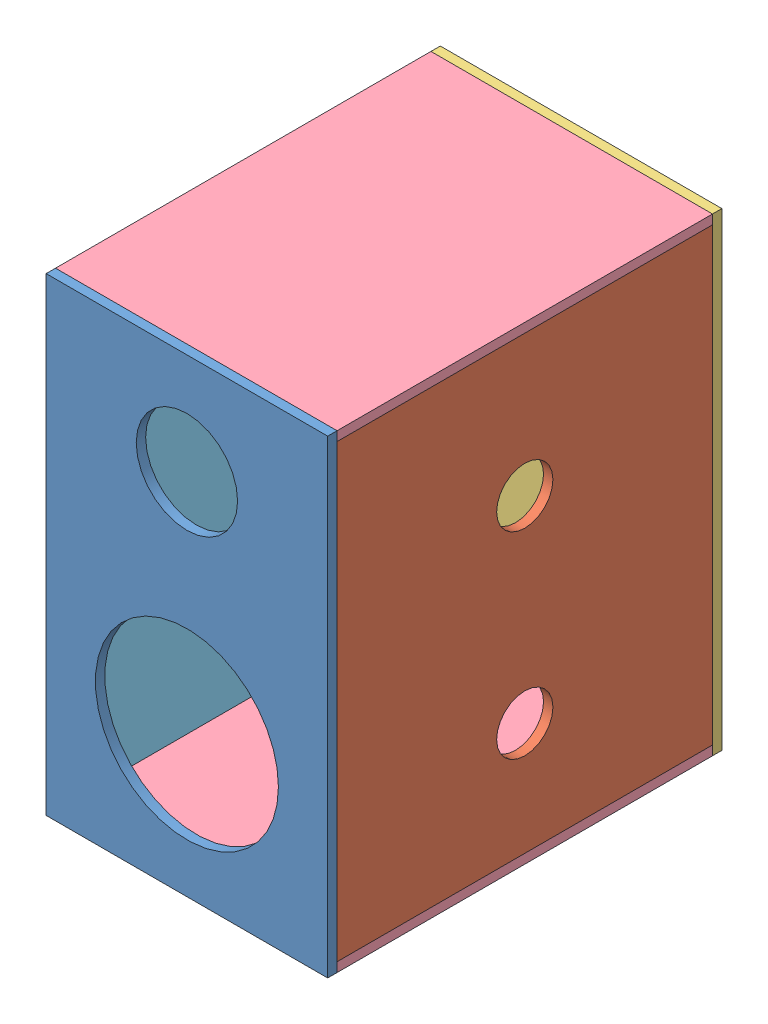
SolidWorks assembly speaker_full, configuration Default. Lengths in mm.
Overall size (300 500 420).
6 component instances, 5 part files, 13 mates.
Components (placement in the parent):
- speaker_front-1: speaker_front [Default] at origin size (300 500 10)
- speaker_int_side-1: speaker_int_side [Default] at (300 10 -410) x (0 0 1) z (-1 0 0) size (400 480 10)
- speaker_rear-1: speaker_rear [Default] at (0 0 -420) size (300 500 10)
- speaker_top_bot-1: speaker_top_bot [Default] at (0 500 -410) x (1 0 0) z (0 -1 0) size (300 400 10)
- speaker_top_bot-2: speaker_top_bot [Default] at (0 10 -410) x (1 0 0) z (0 -1 0) size (300 400 10)
- speaker_ext_side-1: speaker_ext_side [Default] at (10 455.5377 -350.3682) x (0 0 1) z (-1 0 0) size (400 480 10)
Mates (geometry in assembly coordinates):
- Coincident2: coincident aligned: line of speaker_front-1; line of speaker_int_side-1
- Coincident3: coincident anti-aligned: plane of speaker_front-1 through (0 500 -10) normal (0 0 -1); plane of speaker_int_side-1 through (290 10 -10) normal (0 0 1)
- Coincident15: coincident anti-aligned: line of speaker_int_side-1; line of speaker_rear-1
- Coincident19: coincident aligned: plane of speaker_front-1 through (0 500 -10) normal (0 1 0); plane of speaker_rear-1 through (0 500 -410) normal (0 1 0)
- Coincident20: coincident anti-aligned: line of speaker_int_side-1; line of speaker_top_bot-1
- Coincident21: coincident aligned: plane of speaker_rear-1 through (0 500 -410) normal (0 1 0); plane of speaker_top_bot-1 through (0 500 -10) normal (0 1 0)
- Coincident22: coincident: plane of speaker_rear-1 through (0 500 -410) normal (0 0 1); line of speaker_top_bot-1
- Coincident24: coincident anti-aligned: plane of speaker_rear-1 through (0 500 -410) normal (0 0 1); plane of speaker_top_bot-2 through (0 0 -410) normal (0 0 -1)
- Coincident26: coincident aligned: plane of speaker_rear-1 through (0 0 -410) normal (0 -1 0); plane of speaker_top_bot-2 through (0 0 -10) normal (0 -1 0)
- Coincident29: coincident aligned: plane of speaker_int_side-1 through (300 490 -410) normal (1 0 0); plane of speaker_top_bot-2 through (300 0 -410) normal (1 0 0)
- Coincident30: coincident aligned: line of speaker_rear-1; line of speaker_ext_side-1
- Coincident31: coincident anti-aligned: line of speaker_front-1; line of speaker_ext_side-1
- Coincident32: coincident: plane of speaker_top_bot-1 through (0 490 -10) normal (0 -1 0); line of speaker_ext_side-1
